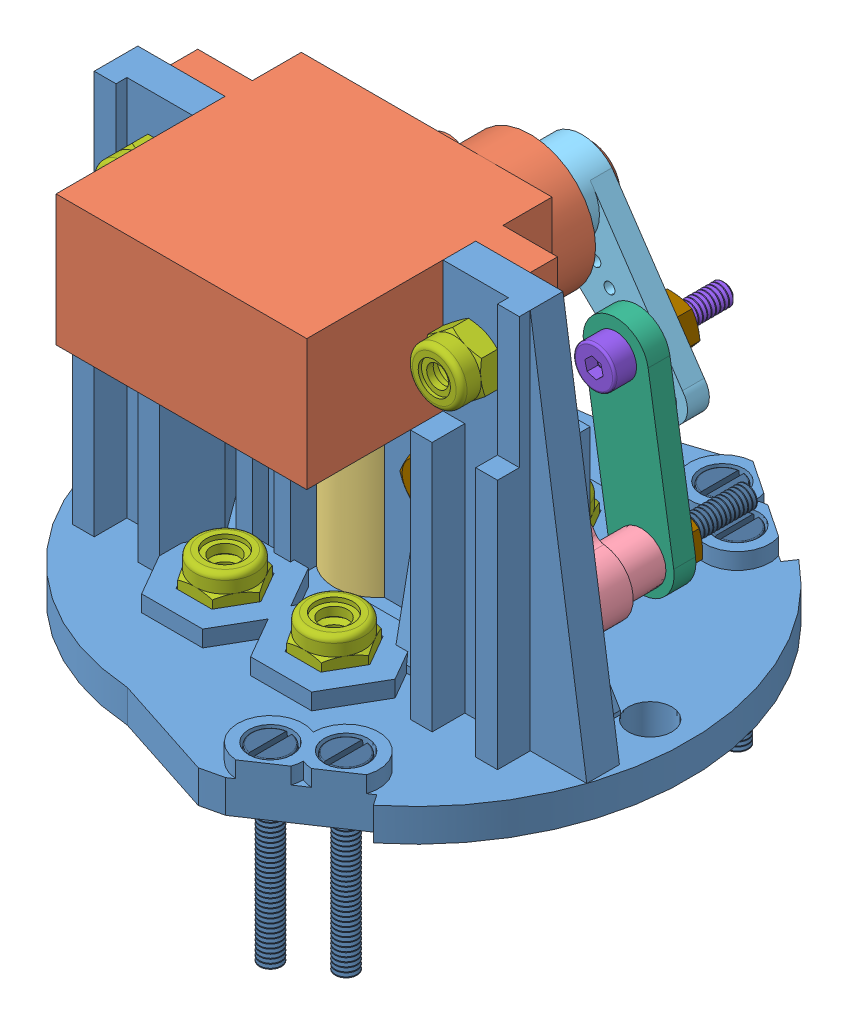
SolidWorks assembly Rückseite, configuration Standard. Lengths in mm.
Overall size (50 51 49.14).
25 component instances, 11 part files, 55 mates.
Components (placement in the parent):
- Backside-1: Backside [Standard] at (-0.7502 -6.4244 50) size (50 38 49.14)
- servo-1: servo [Standard] at (-9.7502 31.5756 70.5) x (1 0 0) z (0 1 0) size (33 29.25 12)
- Druecker-1: Druecker [Standard] at (-0.7502 17.4276 50) x (1 0 0) z (0 0 -1) size (8 31.5 8)
- Hebel-1: Hebel [Standard] at (9.2498 10.5756 51) x (0.961656 -0.27426 0) z (0 0 -1) size (30.92 10.86 7.75)
- Servo-Arm-1: Servo-Arm [Standard] at (7.2498 25.5756 39.25) x (0.645723 -0.763572 0) z (-0.763572 -0.645723 0) size (20.6 4.3 7.2)
- Hebel2-1: Hebel2 [Standard] at (16.7025 2.3615 41.25) x (-0.156647 0.987655 0) z (0.987655 0.156647 0) size (21 2 6)
- User Library-Mutter DIN-985_-1: User Library-Mutter DIN-985_ [Mutter DIN-985 M3-A2] at (-4.7502 -3.4244 60) x (0 1 0) z (0 0 1) size (4 6.35 5.5)
- User Library-Mutter DIN-985_-2: User Library-Mutter DIN-985_ [Mutter DIN-985 M3-A2] at (5.2498 -3.4244 60) x (0 1 0) z (-0.866025 0 0.5) size (4 6.35 5.5)
- User Library-Mutter DIN-985_-3: User Library-Mutter DIN-985_ [Mutter DIN-985 M3-A2] at (5.2498 -3.4244 40) x (0 1 0) z (-0.866025 0 -0.5) size (4 6.35 5.5)
- User Library-Mutter DIN-985_-4: User Library-Mutter DIN-985_ [Mutter DIN-985 M3-A2] at (-4.7502 -3.4244 40) x (0 1 0) z (-0.866025 0 0.5) size (4 6.35 5.5)
- socket head cap screw 4762_din-1: socket head cap screw 4762_din [ISO 4762 M2 x 10 --- 10S] at (9.2498 10.5756 43.8) x (0 0 1) z (0.035285 -0.999377 0) size (12 3.8 3.8)
- socket head cap screw 4762_din-2: socket head cap screw 4762_din [ISO 4762 M2 x 10 --- 10S] at (-0.7502 13.4276 55.5) x (0 0 -1) z (0.060223 0.998185 0) size (12 3.8 3.8)
- socket head cap screw 4762_din-3: socket head cap screw 4762_din [ISO 4762 M2 x 10 --- 10S] at (14.3528 17.1763 45.25) x (0 0 -1) z (-0.686907 0.726745 0) size (12 3.8 3.8)
- nut__style_1__m2x0_4__ansi_b18_2_4_1m-1: nut__style_1__m2x0_4__ansi_b18_2_4_1m [Default] at (-0.7502 13.4276 46.5) x (0.866025 -0.5 0) z (0 0 -1) size (4.62 4 1.6)
- nut__style_1__m2x0_4__ansi_b18_2_4_1m-2: nut__style_1__m2x0_4__ansi_b18_2_4_1m [Default] at (14.3528 17.1763 37.65) x (0.980747 -0.195284 0) z (0 0 1) size (4.62 4 1.6)
- nut__style_1__m2x0_4__ansi_b18_2_4_1m-3: nut__style_1__m2x0_4__ansi_b18_2_4_1m [Default] at (9.2498 10.5756 54.2) x (0.532315 -0.846547 0) z (0 0 1) size (4.62 4 1.6)
- User Library-Mutter DIN-985_-5: User Library-Mutter DIN-985_ [Mutter DIN-985 M2,5-A2] at (-12.7502 25.5756 58) x (0 0 1) z (0.965495 0.260421 0) size (3.8 5.77 5)
- User Library-Mutter DIN-985_-6: User Library-Mutter DIN-985_ [Mutter DIN-985 M2,5-A2] at (16.2498 25.5756 58) x (0 0 1) z (-0.395566 -0.918438 0) size (3.8 5.77 5)
- slotted cheese head screw_din-1: slotted cheese head screw_din [ISO 1207 - M2 x 16 --- 16S] at (10.151 -2.0244 70.7313) x (0 -1 0) z (0 0 1) size (17.41 3.8 3.8)
- slotted cheese head screw_din-2: slotted cheese head screw_din [ISO 1207 - M2 x 16 --- 16S] at (10.151 -2.0244 29.2687) x (0 -1 0) z (0 0 1) size (17.41 3.8 3.8)
- slotted cheese head screw_din-3: slotted cheese head screw_din [ISO 1207 - M2 x 16 --- 16S] at (14.3028 -2.0244 32.0549) x (0 -1 0) z (0 0 1) size (17.41 3.8 3.8)
- slotted cheese head screw_din-4: slotted cheese head screw_din [ISO 1207 - M2 x 16 --- 16S] at (14.3028 -2.0244 67.9451) x (0 -1 0) z (0 0 1) size (17.41 3.8 3.8)
- slotted cheese head screw_din-5: slotted cheese head screw_din [ISO 1207 - M2 x 16 --- 16S] at (16.7025 2.3615 50.85) x (0 0 -1) z (1 0 0) size (17.41 3.8 3.8)
- nut__style_1__m2x0_4__ansi_b18_2_4_1m-4: nut__style_1__m2x0_4__ansi_b18_2_4_1m [Default] at (16.7025 2.3615 41.25) x (0.924405 -0.381413 0) z (0 0 -1) size (4.62 4 1.6)
- cross fh tapping 7976_din-2: cross fh tapping 7976_din [Tapping screw DIN 7982-ST2.9x6.5-C-Z-S] at (7.2498 25.5756 38.5) x (0 0 1) z (-1 0 0) size (6.51 5.5 5.5)
Mates (geometry in assembly coordinates):
- Konzentrisch1: concentric anti-aligned: cylinder of Druecker-1 through (-0.7502 -14.0724 50) axis (0 1 0) radius 4; cylinder of Backside-1 through (-0.7502 -3.4244 50) axis (0 -1 0) radius 4
- Konzentrisch2: concentric aligned: cylinder of Backside-1 through (9.2498 10.5756 57.5) axis (0 0 1) radius 1.15; cylinder of Hebel-1 through (9.2498 10.5756 49) axis (0 0 1) radius 1.15
- Deckungsgleich1: coincident anti-aligned: plane of Hebel-1 through (9.2498 10.5756 49) normal (0 0 -1); plane of Backside-1 through (6.7498 13.5756 49) normal (0 0 1)
- Parallel1: parallel anti-aligned: plane of Druecker-1 through (-5.7502 9.4276 51) normal (0 0 -1); plane of Hebel-1 through (9.2498 10.5756 51) normal (0 0 1)
- Langloch1: slot anti-aligned: cylinder of Druecker-1 through (-0.7502 13.4276 54) axis (0 0 -1) radius 1.1; plane of Hebel-1 through (9.5652 11.6815 49) normal (-0.27426 -0.961656 0); cylinder of Hebel-1 through (-6.1367 14.9638 49) axis (0 0 1) radius 1.15
- Konzentrisch3: concentric anti-aligned: cylinder of servo-1 through (7.2498 25.5756 44) axis (0 0 1) radius 6; cylinder of Servo-Arm-1 through (7.2498 25.5756 43.55) axis (0 0 -1) radius 2.25
- Deckungsgleich6: coincident anti-aligned: plane of Backside-1 through (-9.7502 31.5756 58) normal (1 0 0); plane of servo-1 through (-9.7502 31.5756 48) normal (-1 0 0)
- Deckungsgleich7: coincident anti-aligned: plane of servo-1 through (18.2498 31.5756 55) normal (0 0 1); plane of Backside-1 through (-17.7502 19.5756 55) normal (0 0 -1)
- Deckungsgleich11: coincident aligned: plane of Backside-1 through (-0.7502 31.5756 50) normal (0 1 0); plane of servo-1 through (-9.7502 31.5756 48) normal (0 1 0)
- Deckungsgleich9: coincident anti-aligned: plane of Hebel2-1 through (16.7025 2.3615 41.25) normal (0 0 -1); plane of Servo-Arm-1 through (7.2498 25.5756 41.25) normal (0 0 1)
- Konzentrisch4: concentric anti-aligned: cylinder of Hebel-1 through (16.7025 2.3615 47) axis (0 0 1) radius 1.15; cylinder of Hebel2-1 through (16.7025 2.3615 43.25) axis (0 0 -1) radius 1.15
- Deckungsgleich12: coincident anti-aligned: plane of servo-1 through (7.2498 25.5756 41.25) normal (0 0 -1); plane of Servo-Arm-1 through (7.2498 25.5756 41.25) normal (0 0 1)
- Konzentrisch5: concentric aligned: cylinder of Servo-Arm-1 through (14.3528 17.1763 41.25) axis (0 0 -1) radius 0.5; cylinder of Hebel2-1 through (14.3528 17.1763 43.25) axis (0 0 -1) radius 1.15
- Deckungsgleich28: coincident anti-aligned: plane of Backside-1 through (-0.7502 -3.4244 50) normal (0 1 0); plane of User Library-Mutter DIN-985_-1 through (-7.4789 -3.4244 60) normal (0 -1 0)
- Deckungsgleich29: coincident anti-aligned: plane of Backside-1 through (-0.7502 -3.4244 50) normal (0 1 0); plane of User Library-Mutter DIN-985_-2 through (3.8855 -3.4244 57.6369) normal (0 -1 0)
- Deckungsgleich31: coincident anti-aligned: plane of Backside-1 through (-0.7502 -3.4244 50) normal (0 1 0); plane of User Library-Mutter DIN-985_-3 through (6.6142 -3.4244 37.6369) normal (0 -1 0)
- Deckungsgleich30: coincident anti-aligned: plane of Backside-1 through (-0.7502 -3.4244 50) normal (0 1 0); plane of User Library-Mutter DIN-985_-4 through (-6.1145 -3.4244 37.6369) normal (0 -1 0)
- Deckungsgleich21: coincident anti-aligned: plane of Backside-1 through (9.2498 10.5756 45.8) normal (0 0 -1); plane of socket head cap screw 4762_din-1 through (7.351 10.5086 45.8) normal (0 0 1)
- Konzentrisch20: concentric anti-aligned: cylinder of Backside-1 through (9.2498 10.5756 57.5) axis (0 0 1) radius 1.15; cylinder of socket head cap screw 4762_din-1 through (9.2498 10.5756 12.05) axis (0 0 -1) radius 1
- Konzentrisch19: concentric anti-aligned: cylinder of Druecker-1 through (-0.7502 13.4276 54) axis (0 0 -1) radius 1.1; cylinder of socket head cap screw 4762_din-2 through (-0.7502 13.4276 97.4133) axis (0 0 1) radius 1
- Deckungsgleich38: coincident anti-aligned: plane of Hebel2-1 through (16.7025 2.3615 43.25) normal (0 0 1); plane of socket head cap screw 4762_din-3 through (12.972 15.8712 43.25) normal (0 0 -1)
- Konzentrisch38: concentric anti-aligned: cylinder of Hebel2-1 through (14.3528 17.1763 43.25) axis (0 0 -1) radius 1.15; cylinder of socket head cap screw 4762_din-3 through (14.3528 17.1763 77) axis (0 0 1) radius 1
- Deckungsgleich41: coincident anti-aligned: plane of Druecker-1 through (-0.7502 17.4276 46.5) normal (0 0 -1); plane of nut__style_1__m2x0_4__ansi_b18_2_4_1m-1 through (1.2503 12.2726 46.5) normal (0 0 1)
- Konzentrisch49: concentric aligned: circle of socket head cap screw 4762_din-2; circle of nut__style_1__m2x0_4__ansi_b18_2_4_1m-1
- Deckungsgleich39: coincident anti-aligned: plane of Servo-Arm-1 through (7.2498 25.5756 39.25) normal (0 0 -1); plane of nut__style_1__m2x0_4__ansi_b18_2_4_1m-2 through (16.6183 16.7252 39.25) normal (0 0 1)
- Konzentrisch50: concentric anti-aligned: circle of socket head cap screw 4762_din-3; circle of nut__style_1__m2x0_4__ansi_b18_2_4_1m-2
- Deckungsgleich33: coincident anti-aligned: plane of Backside-1 through (9.2498 10.5756 54.2) normal (0 0 1); plane of nut__style_1__m2x0_4__ansi_b18_2_4_1m-3 through (10.4795 8.6201 54.2) normal (0 0 -1)
- Konzentrisch48: concentric aligned: circle of socket head cap screw 4762_din-1; circle of nut__style_1__m2x0_4__ansi_b18_2_4_1m-3
- Deckungsgleich36: coincident anti-aligned: plane of Backside-1 through (-11.7502 31.5756 58) normal (0 0 1); plane of User Library-Mutter DIN-985_-5 through (-12.1447 23.3307 58) normal (0 0 -1)
- Deckungsgleich37: coincident anti-aligned: plane of Backside-1 through (15.2498 31.5756 58) normal (0 0 1); plane of User Library-Mutter DIN-985_-6 through (14.1143 26.4954 58) normal (0 0 -1)
- Konzentrisch51: concentric aligned: circle of Backside-1; circle of User Library-Mutter DIN-985_-1
- Konzentrisch52: concentric aligned: circle of Backside-1; circle of User Library-Mutter DIN-985_-2
- Konzentrisch53: concentric aligned: circle of Backside-1; circle of User Library-Mutter DIN-985_-4
- Konzentrisch54: concentric aligned: circle of Backside-1; circle of User Library-Mutter DIN-985_-3
- Konzentrisch55: concentric aligned: circle of User Library-Mutter DIN-985_-5; cylinder of Backside-1 through (-12.7502 25.5756 41) axis (0 0 1) radius 1.25
- Konzentrisch56: concentric aligned: circle of User Library-Mutter DIN-985_-6; cylinder of Backside-1 through (16.2498 25.5756 41) axis (0 0 1) radius 1.25
- Deckungsgleich40: coincident anti-aligned: plane of Druecker-1 through (-0.7502 13.4276 53.5) normal (0 0 1); plane of socket head cap screw 4762_din-2 through (-2.6467 13.542 53.5) normal (0 0 -1)
- Konzentrisch59: concentric aligned: cylinder of Backside-1 through (14.3028 -13.4244 32.0549) axis (0 1 0) radius 1.1; cylinder of slotted cheese head screw_din-3 through (14.3028 23.3756 32.0549) axis (0 1 0) radius 1
- Konzentrisch60: concentric aligned: cylinder of Backside-1 through (10.151 -13.4244 29.2687) axis (0 1 0) radius 1.1; cylinder of slotted cheese head screw_din-2 through (10.151 23.3756 29.2687) axis (0 1 0) radius 1
- Konzentrisch61: concentric aligned: cylinder of Backside-1 through (14.3028 -13.4244 67.9451) axis (0 1 0) radius 1.1; cylinder of slotted cheese head screw_din-4 through (14.3028 23.3756 67.9451) axis (0 1 0) radius 1
- Konzentrisch62: concentric aligned: cylinder of Backside-1 through (10.151 -13.4244 70.7313) axis (0 1 0) radius 1.1; cylinder of slotted cheese head screw_din-1 through (10.151 23.3756 70.7313) axis (0 1 0) radius 1
- Deckungsgleich42: coincident anti-aligned: plane of Backside-1 through (-0.7502 -3.4244 50) normal (0 1 0); plane of slotted cheese head screw_din-3 through (15.3028 -3.4244 32.0549) normal (0 -1 0)
- Deckungsgleich43: coincident anti-aligned: plane of Backside-1 through (-0.7502 -3.4244 50) normal (0 1 0); plane of slotted cheese head screw_din-2 through (11.151 -3.4244 29.2687) normal (0 -1 0)
- Deckungsgleich44: coincident anti-aligned: plane of Backside-1 through (-0.7502 -3.4244 50) normal (0 1 0); plane of slotted cheese head screw_din-1 through (11.151 -3.4244 70.7313) normal (0 -1 0)
- Deckungsgleich45: coincident anti-aligned: plane of Backside-1 through (-0.7502 -3.4244 50) normal (0 1 0); plane of slotted cheese head screw_din-4 through (15.3028 -3.4244 67.9451) normal (0 -1 0)
- Konzentrisch64: concentric aligned: cylinder of Hebel-1 through (16.7025 2.3615 47) axis (0 0 1) radius 1.15; cylinder of slotted cheese head screw_din-5 through (16.7025 2.3615 76.25) axis (0 0 1) radius 1
- Deckungsgleich47: coincident aligned: circle of Hebel-1; plane of slotted cheese head screw_din-5 through (16.7025 3.3615 49.45) normal (0 0 -1)
- Deckungsgleich48: coincident anti-aligned: plane of Hebel2-1 through (16.7025 2.3615 41.25) normal (0 0 -1); plane of nut__style_1__m2x0_4__ansi_b18_2_4_1m-4 through (18.8378 1.4805 41.25) normal (0 0 1)
- Konzentrisch65: concentric anti-aligned: cylinder of Hebel2-1 through (16.7025 2.3615 43.25) axis (0 0 -1) radius 1.15; cylinder of nut__style_1__m2x0_4__ansi_b18_2_4_1m-4 through (16.7025 2.3615 41.25) axis (0 0 1) radius 0.7835
- Deckungsgleich50: coincident: circle of Servo-Arm-1; cone of cross fh tapping 7976_din-2 through (7.2498 25.5756 40.2) axis (0 0 1)
- Parallel2: parallel anti-aligned: plane of Backside-1 through (8.5407 -1.9244 40) normal (-0.866025 0 0.5); plane of User Library-Mutter DIN-985_-3 through (8.4252 0.5766 40) normal (0.866025 0 -0.5)
- Parallel3: parallel anti-aligned: plane of Backside-1 through (-1.4593 -1.9244 40) normal (-0.866025 0 0.5); plane of User Library-Mutter DIN-985_-4 through (-1.5748 0.5766 40) normal (0.866025 0 -0.5)
- Parallel4: parallel anti-aligned: plane of Backside-1 through (-3.1047 -1.9244 62.85) normal (-0.866025 0 -0.5); plane of User Library-Mutter DIN-985_-1 through (-3.1625 0.5766 62.75) normal (0.866025 0 0.5)
- Parallel5: parallel anti-aligned: plane of Backside-1 through (6.8953 -1.9244 62.85) normal (-0.866025 0 -0.5); plane of User Library-Mutter DIN-985_-2 through (6.8375 0.5766 62.75) normal (0.866025 0 0.5)
- Parallel6: parallel anti-aligned: plane of Druecker-1 through (-2.8002 14.6111 46.5) normal (0.5 -0.866025 0); plane of nut__style_1__m2x0_4__ansi_b18_2_4_1m-1 through (-2.7507 14.5826 44.9) normal (-0.5 0.866025 0)
